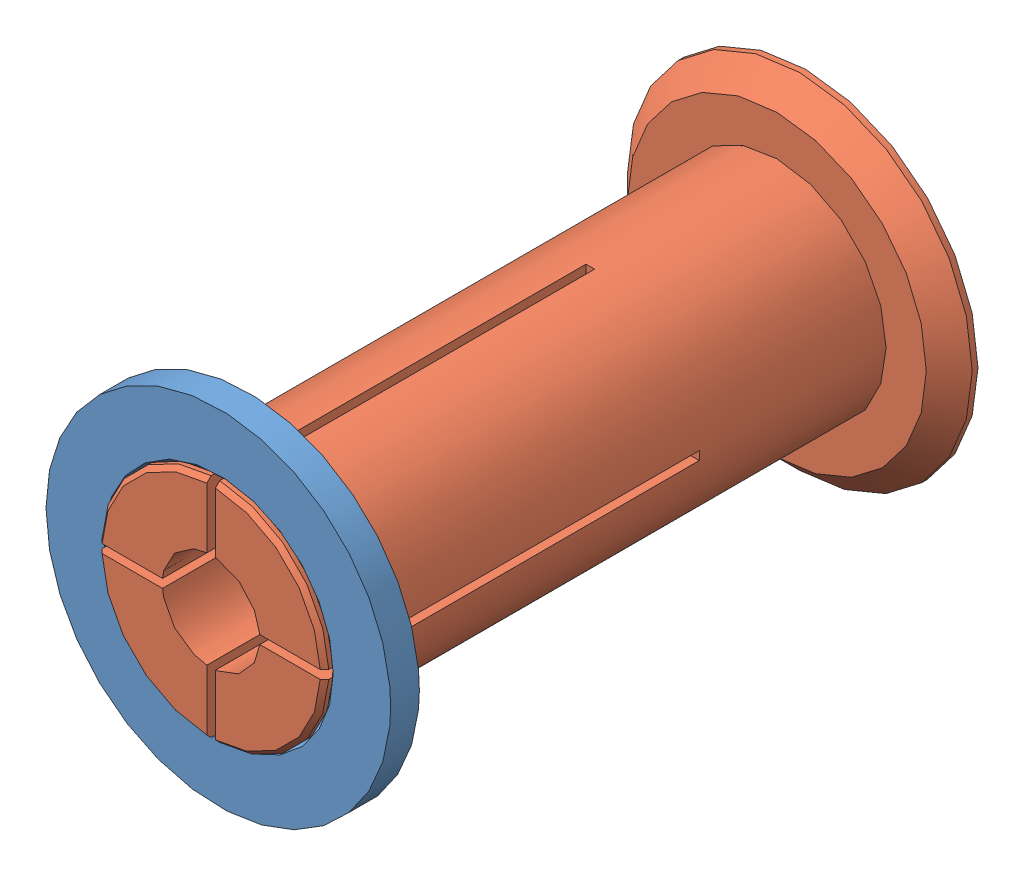
SolidWorks assembly 39-92-17-spool-adapter, configuration Default. Lengths in mm.
Overall size (60 60 103.5).
2 component instances, 2 part files, 2 mates.
Components (placement in the parent):
- 39-92-17-spool-adapter-female-1: 39-92-17-spool-adapter-female [Default] at (16.0809 35.0752 44.3306) size (60 60 5)
- 39-92-17-spool-adapter-male-1: 39-92-17-spool-adapter-male [Default] at (16.0809 35.0752 -47.9194) size (60 60 103.5)
Mates (geometry in assembly coordinates):
- Concentric1: concentric anti-aligned: cylinder of 39-92-17-spool-adapter-female-1 through (16.0809 35.0752 44.3306) axis (0 0 1) radius 19.25; cylinder of 39-92-17-spool-adapter-male-1 through (16.0809 35.0752 50.5806) axis (0 0 -1) radius 19
- Coincident1: coincident aligned: cone of 39-92-17-spool-adapter-female-1 through (16.0809 35.0752 49.3306) axis (0 0 -1); cone of 39-92-17-spool-adapter-male-1 through (16.0809 35.0752 49.0806) axis (0 0 -1)
